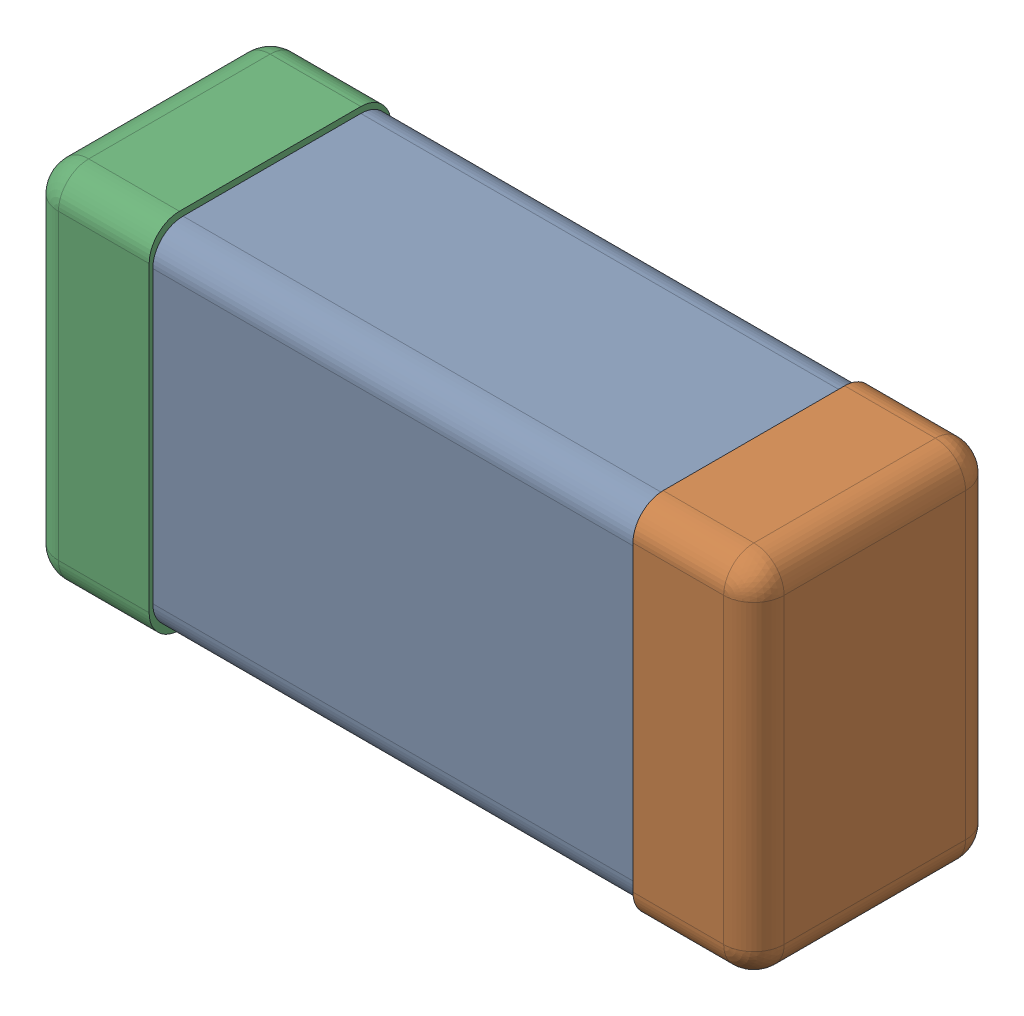
SolidWorks assembly C0201_020_25, configuration Standard. Lengths in mm.
Overall size (0.6 0.3 0.2).
3 component instances, 3 part files, 0 mates.
Components (placement in the parent):
- Part 3_2-1: Part 3_2 [Standard] at (0 0 -7.3015) size (0.5 0.29 0.2)
- Part 2_2-1: Part 2_2 [Standard] at (0 0 -7.3) size (0.1 0.3 0.2)
- Part 1_2-1: Part 1_2 [Standard] at (0 0 -7.3) size (0.1 0.3 0.2)
